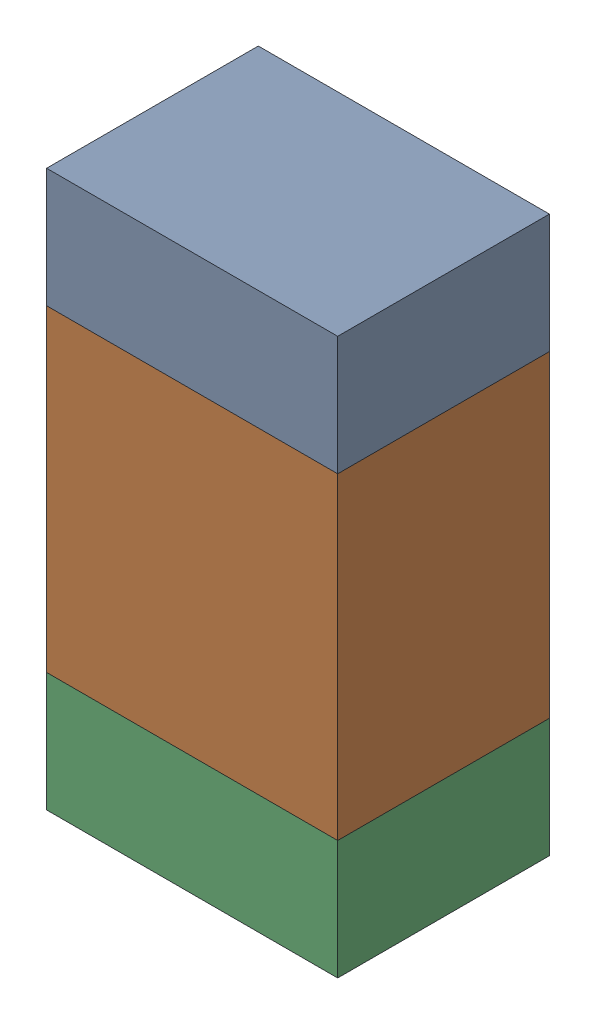
SolidWorks assembly R302_2PCB, configuration Default. Lengths in mm.
Overall size (0.55 1.05 0.4).
6 component instances, 2 part files, 0 mates.
Components (placement in the parent):
- 846483288-1: 846483288 [Default] at (144.2999 89.5126 0) size (0.55 0.22 0.4)
  - Extruded_12-1: Extruded_12 [Default] at origin size (0.55 0.22 0.4)
- 846483424-1: 846483424 [Default] at (144.2999 89.1001 0) size (0.55 0.6 0.4)
  - Extruded_13-1: Extruded_13 [Default] at origin size (0.55 0.6 0.4)
- 846483288-2: 846483288 [Default] at (144.2999 88.6876 0) size (0.55 0.22 0.4)
  - Extruded_12-1: Extruded_12 [Default] at origin size (0.55 0.22 0.4)
